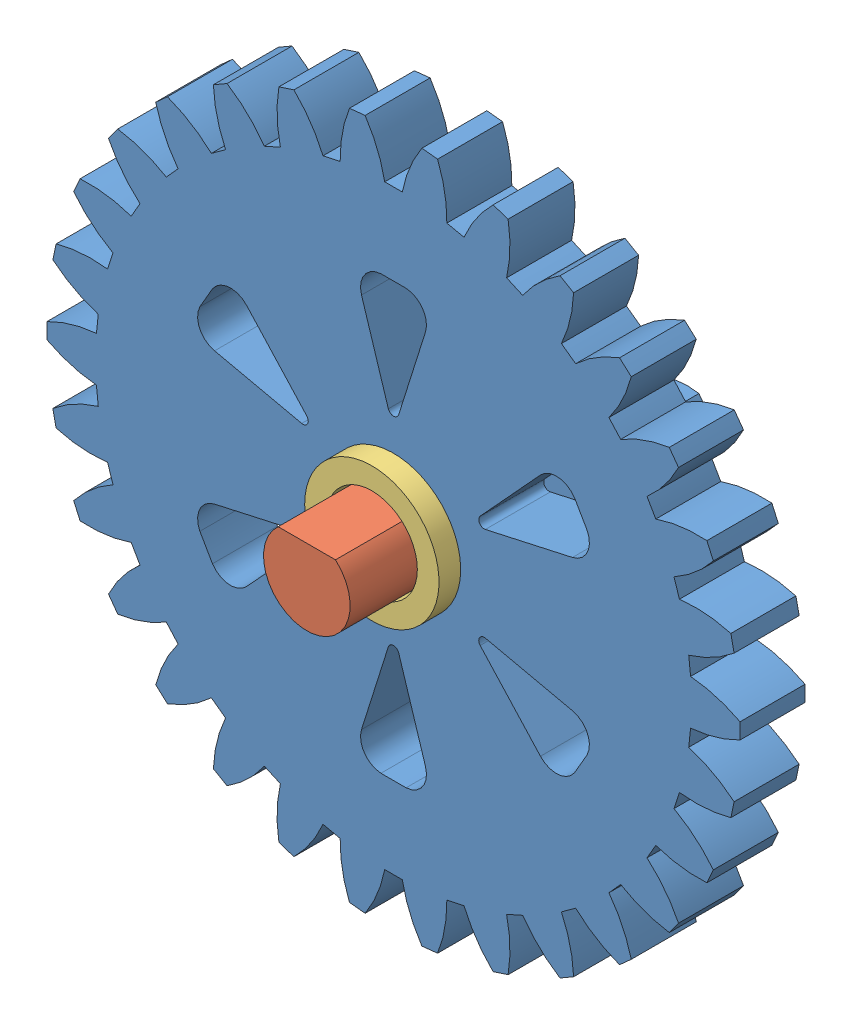
SolidWorks assembly second subassembly, configuration Default. Lengths in mm.
Overall size (32 31.89 15).
6 component instances, 3 part files, 14 mates.
Components (placement in the parent):
- root_gear copy-1: root_gear copy [30T 1.0Mod] at (4.5377 7.1173 5.4193) size (32 31.89 3)
- root_gear copy-2: root_gear copy [10T 1.5Mod] at (4.5377 7.1173 4.4193) x (-1 0 0) z (0 0 -1) size (18 17.3 3)
- axle-1: axle [15 mm tall] at (4.5377 7.1173 -2.5807) size (4 3.5 15)
- spacer-1: spacer [4.2 mm ID] at (4.5377 7.1173 4.4193) size (6.2 6.2 1)
- spacer-2: spacer [4.2 mm ID] at (4.5377 7.1173 0.4193) size (6.2 6.2 1)
- spacer-3: spacer [4.2 mm ID] at (4.5377 7.1173 8.4193) size (6.2 6.2 1)
Mates (geometry in assembly coordinates):
- Parallel3: parallel anti-aligned: plane of root_gear copy-1 through (3.2148 8.6173 -1.5807) normal (0 -1 0); plane of axle-1 through (3.2148 8.6173 12.4193) normal (0 1 0)
- Coincident14: coincident anti-aligned: plane of root_gear copy-1 through (3.2148 8.6173 -1.5807) normal (0 -1 0); plane of axle-1 through (3.2148 8.6173 12.4193) normal (0 1 0)
- Coincident15: coincident anti-aligned: circle of root_gear copy-1; cylinder of axle-1 through (4.5377 7.1173 12.4193) axis (0 0 -1) radius 2
- Parallel4: parallel anti-aligned: plane of root_gear copy-2 through (5.8606 8.6173 11.4193) normal (0 -1 0); plane of axle-1 through (3.2148 8.6173 12.4193) normal (0 1 0)
- Coincident17: coincident anti-aligned: plane of root_gear copy-2 through (5.8606 8.6173 11.4193) normal (0 -1 0); plane of axle-1 through (3.2148 8.6173 12.4193) normal (0 1 0)
- Concentric1: concentric aligned: cylinder of root_gear copy-2 through (4.5377 7.1173 11.4193) axis (0 0 -1) radius 2; cylinder of axle-1 through (4.5377 7.1173 12.4193) axis (0 0 -1) radius 2
- Concentric2: concentric aligned: cylinder of axle-1 through (4.5377 7.1173 12.4193) axis (0 0 -1) radius 2; cylinder of spacer-2 through (4.5377 7.1173 1.4193) axis (0 0 -1) radius 2.1
- Coincident20: coincident anti-aligned: plane of root_gear copy-1 through (4.5377 7.1173 5.4193) normal (0 0 -1); plane of spacer-1 through (4.5377 7.1173 5.4193) normal (0 0 1)
- Concentric3: concentric aligned: cylinder of axle-1 through (4.5377 7.1173 12.4193) axis (0 0 -1) radius 2; cylinder of spacer-1 through (4.5377 7.1173 5.4193) axis (0 0 -1) radius 2.1
- Coincident21: coincident anti-aligned: plane of root_gear copy-2 through (4.5377 7.1173 4.4193) normal (0 0 1); plane of spacer-1 through (4.5377 7.1173 4.4193) normal (0 0 -1)
- Coincident22: coincident anti-aligned: plane of root_gear copy-1 through (4.5377 7.1173 8.4193) normal (0 0 1); plane of spacer-3 through (4.5377 7.1173 8.4193) normal (0 0 -1)
- Concentric4: concentric anti-aligned: cylinder of root_gear copy-1 through (4.5377 7.1173 -1.5807) axis (0 0 1) radius 2; circle of spacer-3
- Distance1: distance = 3 mm aligned: plane of axle-1 through (4.5377 7.1173 -2.5807) normal (0 0 -1); plane of spacer-2 through (4.5377 7.1173 0.4193) normal (0 0 -1)
- Coincident27: coincident anti-aligned: plane of root_gear copy-2 through (4.5377 7.1173 1.4193) normal (0 0 -1); plane of spacer-2 through (4.5377 7.1173 1.4193) normal (0 0 1)
